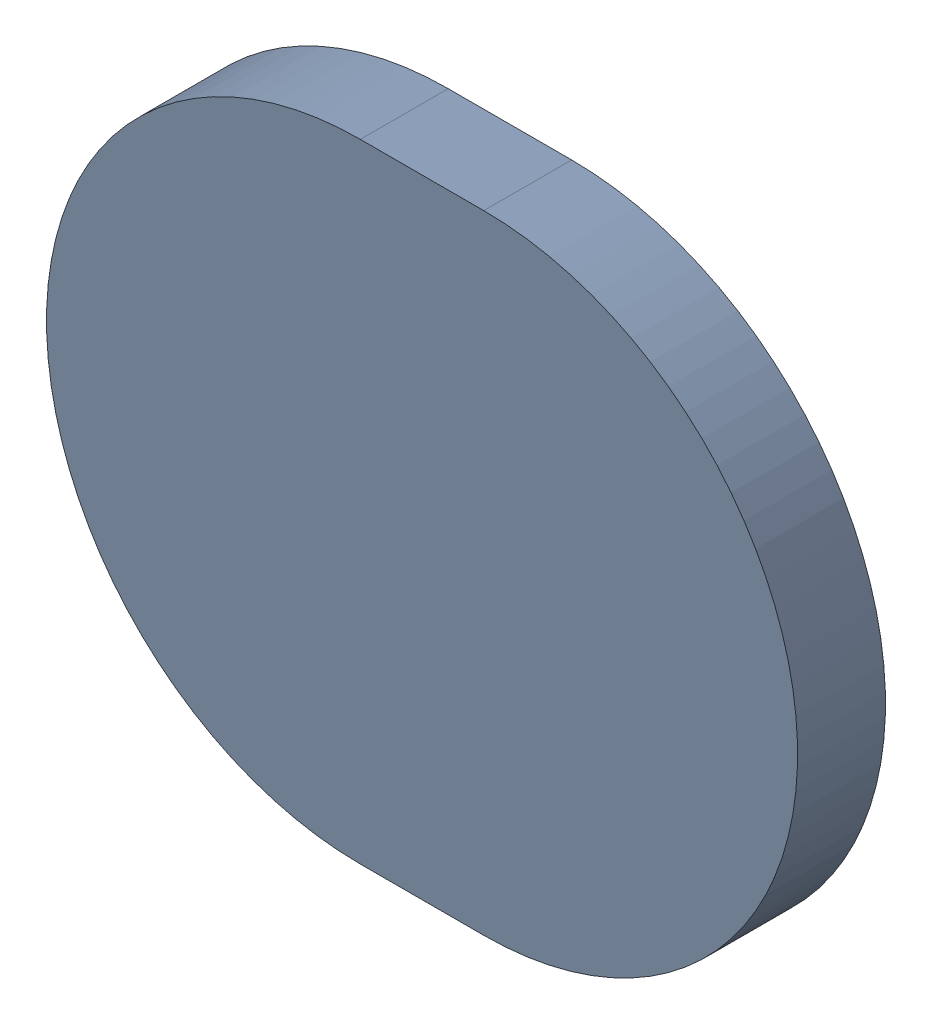
SolidWorks assembly Track (31mm,40mm)(31.05mm,40mm) on Top Layer, configuration Predeterminado. Lengths in mm.
Overall size (0.3 0.25 0.04).
2 component instances, 1 part files, 0 mates.
Components (placement in the parent):
- Track (31mm,40mm)(31.05mm,40mm) on Top Layer-1-1: Track (31mm,40mm)(31.05mm,40mm) on Top Layer-1 [Predeterminado] at (-68.317 -44.187 -0.0457) size (0.3 0.25 0.04)
  - Track (31mm,40mm)(31.05mm,40mm) on Top Layer-Part-1-1: Track (31mm,40mm)(31.05mm,40mm) on Top Layer-Part-1 [Predeterminado] at origin size (0.3 0.25 0.04)
